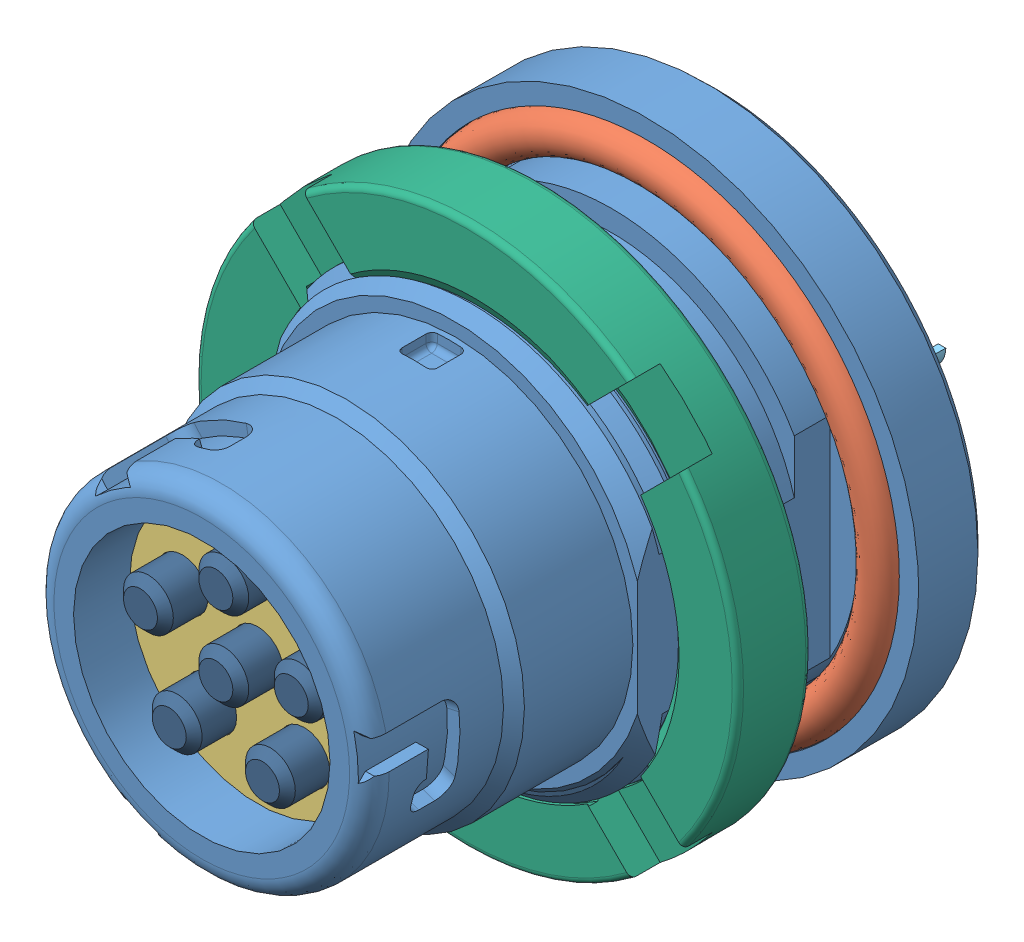
SolidWorks assembly M55116_10-0 v7, configuration Default. Lengths in mm.
Overall size (34.41 34.41 29.28).
42 component instances, 10 part files, 0 mates.
Components (placement in the parent):
- Housing Metal-1: Housing Metal [Default] at (73.025 80.137 -6.223) size (24.34 24.34 23.04)
- O-Ring - Outer-1: O-Ring - Outer [Default] at (73.025 80.137 -6.223) size (22.61 22.61 1.78)
- Plastic Housing - Upper-1: Plastic Housing - Upper [Default] at (73.025 80.137 -6.223) size (13.16 13.16 16.89)
- Plastic Housing - Lower-1: Plastic Housing - Lower [Default] at (73.025 80.137 -6.223) size (13.16 13.16 3.81)
- Solder Cup-1: Solder Cup [Default] at (73.025 80.137 -6.223) size (2.79 2.79 11.66)
- Retaining Nut-1: Retaining Nut [Default] at (73.025 80.137 -5.7404) x (-0.707107 0.707107 0) z (0 0 1) size (24.33 24.33 3.32)
- O-Ring - Inner-1: O-Ring - Inner [Default] at (73.025 80.137 -6.223) size (13.46 13.46 2.54)
- Pogo Spring Asmbly-1: Pogo Spring Asmbly [Default] at origin size (2.95 2.95 19.03)
  - Pogo Spring-1: Pogo Spring [Default] at (73.025 80.137 -6.223) size (2.88 2.88 16.26)
  - Pogo Pin Asmbly-1: Pogo Pin Asmbly [Default] at origin size (2.95 2.95 7.62)
    - Pogo O-Ring-1: Pogo O-Ring [Default] at (73.025 80.137 -6.223) size (2.92 2.92 0.76)
    - Pogo Contact Pin-1: Pogo Contact Pin [Default] at (73.025 80.137 -6.223) size (2.95 2.95 7.62)
- Solder Cup-2: Solder Cup [Default] at (73.025 83.693 -6.223) size (2.79 2.79 11.66)
- Pogo Spring Asmbly_2-1: Pogo Spring Asmbly_2 [Default] at (0 12.7 0) size (2.95 2.95 19.03)
  - Pogo Spring-1: Pogo Spring [Default] at (73.025 70.993 -6.223) size (2.88 2.88 16.26)
  - Pogo Pin Asmbly_2-1: Pogo Pin Asmbly_2 [Default] at origin size (2.95 2.95 7.62)
    - Pogo O-Ring-1: Pogo O-Ring [Default] at (73.025 70.993 -6.223) size (2.92 2.92 0.76)
    - Pogo Contact Pin-1: Pogo Contact Pin [Default] at (73.025 70.993 -6.223) size (2.95 2.95 7.62)
- Pogo Spring Asmbly_3-1: Pogo Spring Asmbly_3 [Default] at (0 19.05 0) size (2.95 2.95 19.03)
  - Pogo Spring-1: Pogo Spring [Default] at (69.643 62.1859 -6.223) size (2.88 2.88 16.26)
  - Pogo Pin Asmbly_3-1: Pogo Pin Asmbly_3 [Default] at origin size (2.95 2.95 7.62)
    - Pogo O-Ring-1: Pogo O-Ring [Default] at (69.643 62.1859 -6.223) size (2.92 2.92 0.76)
    - Pogo Contact Pin-1: Pogo Contact Pin [Default] at (69.643 62.1859 -6.223) size (2.95 2.95 7.62)
- Solder Cup-3: Solder Cup [Default] at (69.643 81.2359 -6.223) size (2.79 2.79 11.66)
- Pogo Spring Asmbly_4-1: Pogo Spring Asmbly_4 [Default] at (0 25.4 0) size (2.95 2.95 19.03)
  - Pogo Spring-1: Pogo Spring [Default] at (70.9348 51.8601 -6.223) size (2.88 2.88 16.26)
  - Pogo Pin Asmbly_4-1: Pogo Pin Asmbly_4 [Default] at origin size (2.95 2.95 7.62)
    - Pogo O-Ring-1: Pogo O-Ring [Default] at (70.9348 51.8601 -6.223) size (2.92 2.92 0.76)
    - Pogo Contact Pin-1: Pogo Contact Pin [Default] at (70.9348 51.8601 -6.223) size (2.95 2.95 7.62)
- Solder Cup-4: Solder Cup [Default] at (70.9348 77.2601 -6.223) size (2.79 2.79 11.66)
- Pogo Spring Asmbly_5-1: Pogo Spring Asmbly_5 [Default] at (0 31.75 0) size (2.95 2.95 19.03)
  - Pogo Spring-1: Pogo Spring [Default] at (75.1152 45.5101 -6.223) size (2.88 2.88 16.26)
  - Pogo Pin Asmbly_5-1: Pogo Pin Asmbly_5 [Default] at origin size (2.95 2.95 7.62)
    - Pogo O-Ring-1: Pogo O-Ring [Default] at (75.1152 45.5101 -6.223) size (2.92 2.92 0.76)
    - Pogo Contact Pin-1: Pogo Contact Pin [Default] at (75.1152 45.5101 -6.223) size (2.95 2.95 7.62)
- Solder Cup-5: Solder Cup [Default] at (75.1152 77.2601 -6.223) size (2.79 2.79 11.66)
- Pogo Spring Asmbly_6-1: Pogo Spring Asmbly_6 [Default] at (0 38.1 0) size (2.95 2.95 19.03)
  - Pogo Spring-1: Pogo Spring [Default] at (76.407 43.1359 -6.223) size (2.88 2.88 16.26)
  - Pogo Pin Asmbly_6-1: Pogo Pin Asmbly_6 [Default] at origin size (2.95 2.95 7.62)
    - Pogo O-Ring-1: Pogo O-Ring [Default] at (76.407 43.1359 -6.223) size (2.92 2.92 0.76)
    - Pogo Contact Pin-1: Pogo Contact Pin [Default] at (76.407 43.1359 -6.223) size (2.95 2.95 7.62)
- Solder Cup-6: Solder Cup [Default] at (76.4187 81.1885 -6.1973) size (2.79 2.79 11.66)
